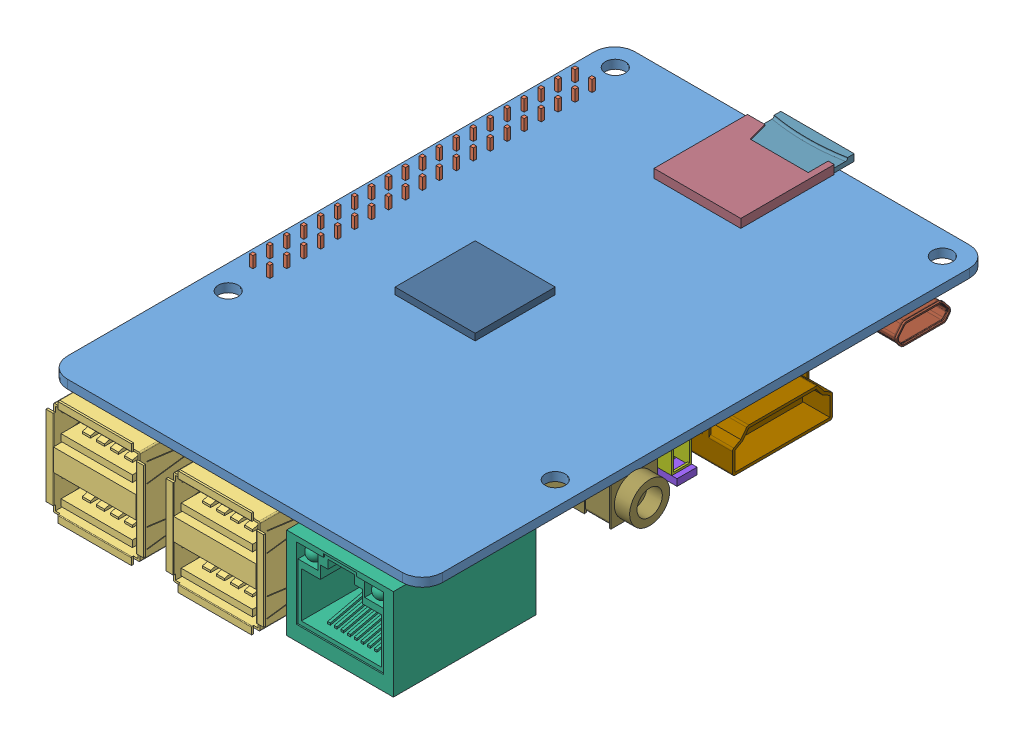
SolidWorks assembly RaspberryPi2, configuration Défaut. Lengths in mm.
Overall size (58.5 19 89.3).
19 component instances, 14 part files, 0 mates.
Components (placement in the parent):
- Mainboard-1: Mainboard [Défaut] at (13.5739 -1.7668 0) size (56.2 1.3 85)
- GPIO-1: GPIO [Défaut] at (-10.9261 -1.7668 -11.37) x (1 0 0) z (0 0 -1) size (5 11.5 50.8)
- USB-1: USB [Défaut] at (-5.3261 -9.8668 27.6) x (1 0 0) z (0 -1 0) size (14.6 17 16)
- USB-2: USB [Défaut] at (12.6739 -9.8668 27.6) x (1 0 0) z (0 -1 0) size (14.6 17 16)
- Processor-1: Processor [Défaut] at (10.1739 -1.7668 -15.5) x (1 0 0) z (0 0 -1) size (14 1 14)
- GPU-1: GPU [Défaut] at (7.7239 -1.7668 17.25) x (1 0 0) z (0 0 -1) size (9.1 1 9.1)
- RJ45-1: RJ45 [Défaut] at (31.1739 -1.7668 33.65) x (1 0 0) z (0 0 -1) size (16 13.7 21.4)
- CameraAssembly-1: CameraAssembly [Défaut] at (30.2239 1.149 9.8385) x (0 0 -1) z (-1 0 0) size (5 5.5 22.1)
  - Camera-1: Camera [Défaut] at (7.3885 2.9159 0) size (5 5.5 20.5)
  - CameraTop-1: CameraTop [Défaut] at (6.8885 8.4159 0) x (1 0 0) z (0 0 -1) size (4 1 22.1)
- CameraAssembly-2: CameraAssembly [Défaut] at (13.4239 1.149 -45.3885) x (0 0 1) z (1 0 0) size (5 5.5 22.1)
  - Camera-1: Camera [Défaut] at (7.3885 2.9159 0) size (5 5.5 20.5)
  - CameraTop-1: CameraTop [Défaut] at (6.8885 8.4159 0) x (1 0 0) z (0 0 -1) size (4 1 22.1)
- HDMI-1: HDMI [Défaut] at (31.6739 -6.4341 -9.95) x (0 1 0) z (0 0 -1) size (6.5 11.5 15)
- RAM-1: RAM [Défaut] at (8.0739 0.5332 1) x (1 0 0) z (0 0 -1) size (12 1 12)
- MicroUSB-1: MicroUSB [Défaut] at (42.6739 -3.4668 -31.6) x (0 1 0) z (0 0 1) size (3 6 8)
- Audio-1: Audio [Défaut] at (35.4239 -1.7668 10.75) x (0 0 1) z (1 0 0) size (7 6 14.8)
- MicroSDSocket-1: MicroSDSocket [Défaut] at (12.8739 -0.4668 -34.5) x (-1 0 0) z (0 0 -1) size (13 1.3 14)
- MicroSD-1: MicroSD [Défaut] at (13.6739 0.1832 -37.2) x (1 0 0) z (0 0 -1) size (11.29 1 15)
